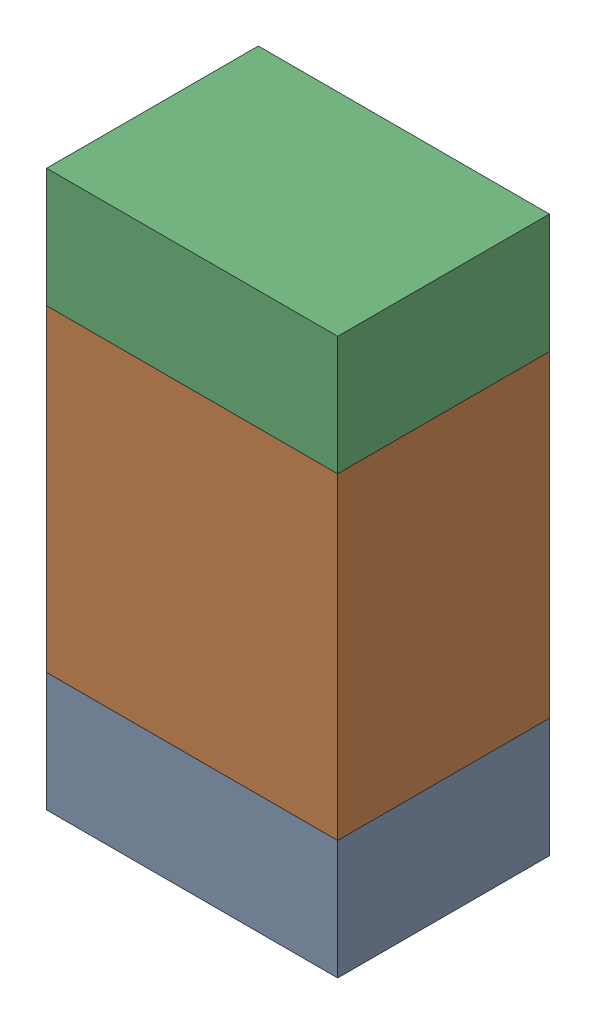
SolidWorks assembly R604_2PCB, configuration Default. Lengths in mm.
Overall size (0.55 1.05 0.4).
6 component instances, 2 part files, 0 mates.
Components (placement in the parent):
- 846483288-1: 846483288 [Default] at (100.0001 106.7876 -2.0638) size (0.55 0.22 0.4)
  - Extruded_12-1: Extruded_12 [Default] at origin size (0.55 0.22 0.4)
- 846483424-1: 846483424 [Default] at (100.0001 107.2001 -2.0638) size (0.55 0.6 0.4)
  - Extruded_13-1: Extruded_13 [Default] at origin size (0.55 0.6 0.4)
- 846483288-2: 846483288 [Default] at (100.0001 107.6126 -2.0638) size (0.55 0.22 0.4)
  - Extruded_12-1: Extruded_12 [Default] at origin size (0.55 0.22 0.4)
